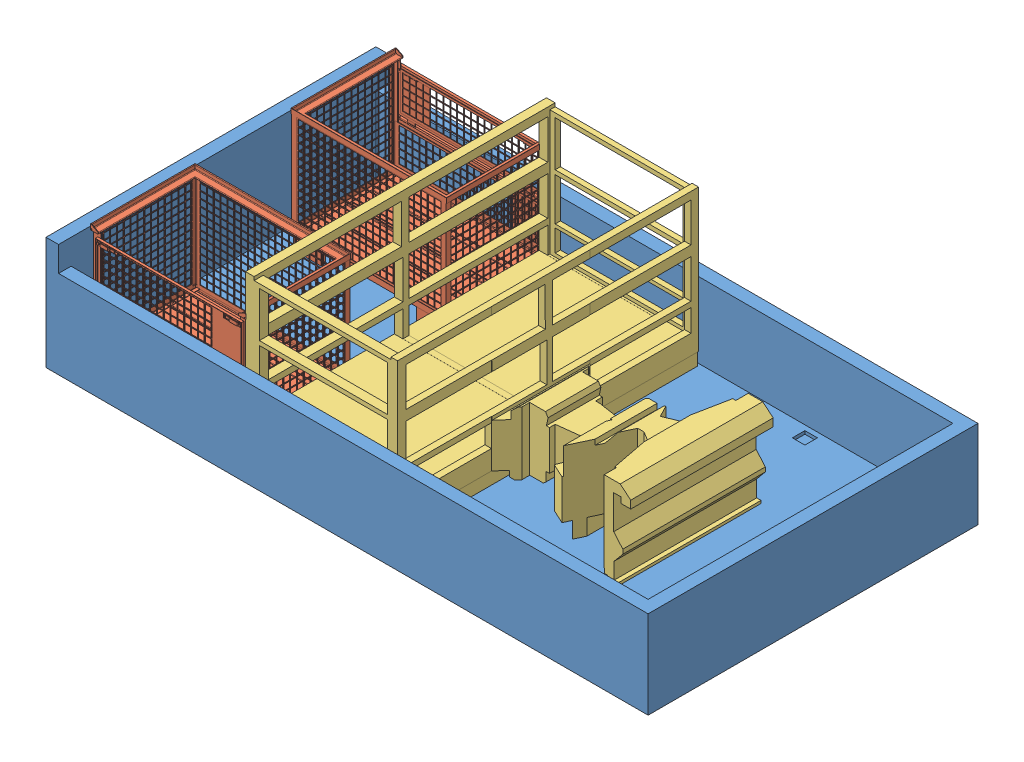
SolidWorks assembly Tetris, configuration Standard. Lengths in mm.
Overall size (4800 1357.88 2630).
4 component instances, 3 part files, 12 mates.
Components (placement in the parent):
- Ladeflaeche-1: Ladeflaeche [Standard] at (4700 0 2530) size (4800 900 2630)
- User Library-GITTERBOX_DIN15155-1: User Library-GITTERBOX_DIN15155 [Standard] at (875 100 515.5) x (-1 0 0) z (0 0 -1) size (1240 970 837.49)
- User Library-GITTERBOX_DIN15155-2: User Library-GITTERBOX_DIN15155 [Standard] at (875 100 2114.5) size (1240 970 837.49)
- Korb-1: Korb [Standard] at (1435.7164 88.231 130) x (0 0 1) z (-1 0 0) size (2400 1262.65 2495.72)
Mates (geometry in assembly coordinates):
- Deckungsgleich1: coincident anti-aligned: plane of Ladeflaeche-1 through (0 0 0) normal (0 0 -1); plane of assembly through (0 0 0) normal (0 0 1)
- Deckungsgleich2: coincident anti-aligned: plane of Ladeflaeche-1 through (4700 0 2530) normal (0 -1 0); plane of assembly through (0 0 0) normal (0 1 0)
- Deckungsgleich3: coincident anti-aligned: plane of Ladeflaeche-1 through (0 0 2630) normal (-1 0 0); plane of assembly through (0 0 0) normal (1 0 0)
- Deckungsgleich4: coincident aligned: plane of Ladeflaeche-1 through (260 75 240) normal (-1 0 0); plane of User Library-GITTERBOX_DIN15155-1 through (260 200 120) normal (-1 0 0)
- Deckungsgleich5: coincident anti-aligned: plane of Ladeflaeche-1 through (4700 100 2530) normal (0 1 0); plane of User Library-GITTERBOX_DIN15155-1 through (492 100 929.5) normal (0 -1 0)
- Deckungsgleich7: coincident anti-aligned: plane of Ladeflaeche-1 through (100 0 100) normal (0 0 1); plane of User Library-GITTERBOX_DIN15155-1 through (289.5 344 100) normal (0 0 -1)
- Deckungsgleich8: coincident aligned: plane of Ladeflaeche-1 through (260 75 2490) normal (-1 0 0); plane of User Library-GITTERBOX_DIN15155-2 through (260 245 2510) normal (-1 0 0)
- Deckungsgleich9: coincident anti-aligned: plane of Ladeflaeche-1 through (4700 100 2530) normal (0 1 0); plane of User Library-GITTERBOX_DIN15155-2 through (278 100 1799.5) normal (0 -1 0)
- Deckungsgleich10: coincident anti-aligned: plane of Ladeflaeche-1 through (100 0 2530) normal (0 0 -1); plane of User Library-GITTERBOX_DIN15155-2 through (264.5 344 2530) normal (0 0 1)
- Deckungsgleich11: coincident: plane of Ladeflaeche-1 through (4700 100 2530) normal (0 1 0); plane of Korb-1 through (1436.2571 -379.4979 2800.39) normal (0 -1 0)
- Deckungsgleich13: coincident: plane of Ladeflaeche-1 through (100 0 2530) normal (0 0 -1); plane of Korb-1 through (1436.2571 -391.2669 2800.39) normal (0 0 1)
- Deckungsgleich15: coincident anti-aligned: plane of User Library-GITTERBOX_DIN15155-2 through (1490 247 1737) normal (1 0 0); plane of Korb-1 through (1490 88.231 2530) normal (-1 0 0)
